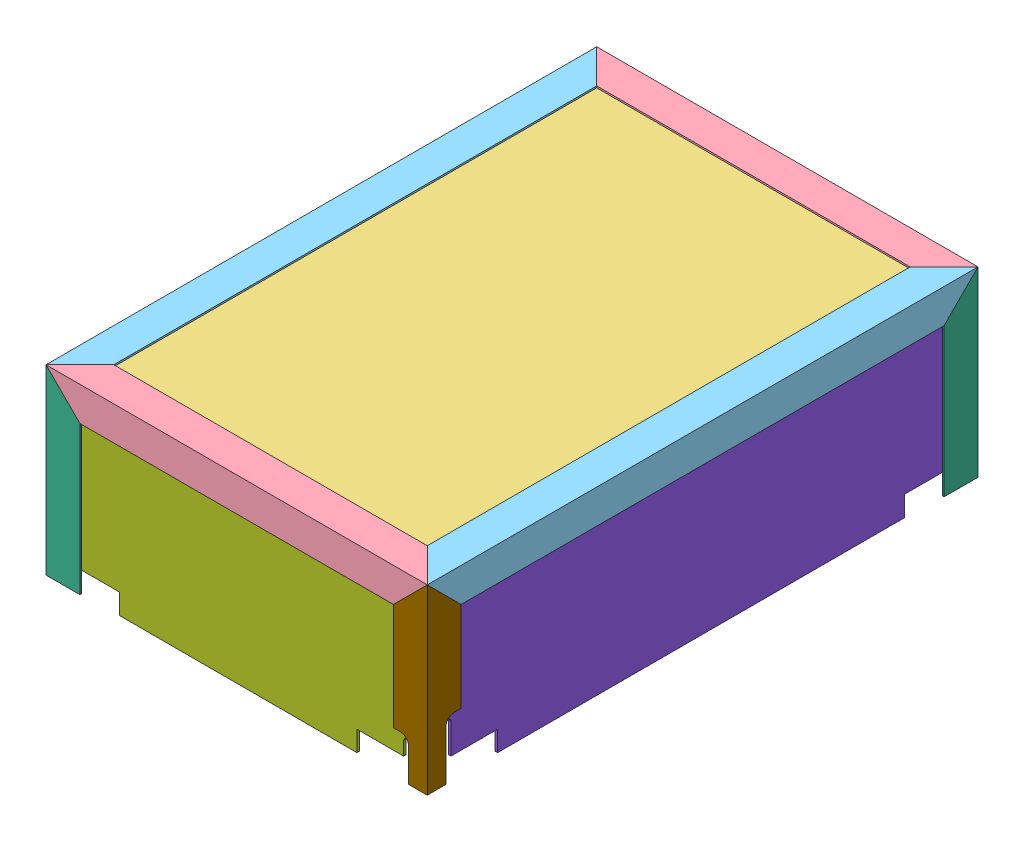
SolidWorks assembly couvercle, configuration Défaut. Lengths in mm.
Overall size (450 215 650).
13 component instances, 9 part files, 31 mates.
Components (placement in the parent):
- plaque_acrylique_680x210-2: plaque_acrylique_680x210 [Défaut] at (-583.1966 1.1201 -270.8343) x (0 0 -1) z (1 0 0) size (640 210 3)
- plaque_acrylique_380x210-2: plaque_acrylique_380x210 [Défaut] at (-330.1966 1.1201 -613.8343) size (440 210 3)
- plaque_acrylique_380x680-1: plaque_acrylique_380x680 [Défaut] at (-330.1966 106.1201 -270.8343) x (1 0 0) z (0 1 0) size (440 640 3)
- eclisse_40x40x404_bisote_x2-1: eclisse_40x40x404_bisote_x2 [Défaut] at (-135.1966 91.0065 -595.8343) x (0 0 1) z (0 -1 0) size (40 450 40)
- eclisse_40x40x704_bisote_x2-1: eclisse_40x40x704_bisote_x2 [Défaut] at (-155.3102 91.1201 -615.8343) x (0 -1 0) z (-1 0 0) size (40 650 40)
- eclisse_40x40x404_bisote_x2-2: eclisse_40x40x404_bisote_x2 [Défaut] at (-585.1966 91.0065 14.1657) x (0 0 -1) z (0 -1 0) size (40 450 40)
- eclisse_40x40x704_bisote_x2-2: eclisse_40x40x704_bisote_x2 [Défaut] at (-565.1966 91.0065 -615.8343) x (1 0 0) z (0 -1 0) size (40 650 40)
- eclisse_40x40x222_bisote_x1-1: eclisse_40x40x222_bisote_x1 [Défaut] at (-565.083 111.1201 -595.8343) x (0 0 1) z (1 0 0) size (40 215 40)
- eclisse_40x40x222_bisote_x1-2: eclisse_40x40x222_bisote_x1 [Défaut] at (-155.1966 111.1201 -595.7207) x (-1 0 0) z (0 0 1) size (40 215 40)
- eclisse_40x40x222_bisote_x1-4: eclisse_40x40x222_bisote_x1 [Défaut] at (-565.1966 111.1201 14.052) x (1 0 0) z (0 0 -1) size (40 215 40)
- plaque_acrylique_380x210_Moteur-1: plaque_acrylique_380x210_Moteur [Défaut] at (-330.1966 1.1201 29.1657) size (440 210 3)
- plaque_acrylique_680x210_moteur-1: plaque_acrylique_680x210_moteur [Défaut] at (-140.1966 1.1201 -270.8343) x (0 0 -1) z (1 0 0) size (640 210 3)
- eclisse_40x40x222_bisote_x1_Moteur-1: eclisse_40x40x222_bisote_x1_Moteur [Défaut] at (-155.3102 111.1201 14.1657) x (0 0 -1) z (-1 0 0) size (40 215 40)
Mates (geometry in assembly coordinates):
- Coïncidente1: coincident anti-aligned: plane of plaque_acrylique_380x680-1 through (-330.1966 109.1201 -270.8343) normal (0 1 0); plane of eclisse_40x40x704_bisote_x2-1 through (-137.1966 109.1201 34.1657) normal (0 -1 0)
- Coïncidente2: coincident anti-aligned: plane of eclisse_40x40x704_bisote_x2-1 through (-137.1966 109.1201 34.1657) normal (-1 0 0); plane of plaque_acrylique_680x210_moteur-1 through (-137.1966 1.1201 -270.8343) normal (1 0 0)
- Coïncidente3: coincident anti-aligned: plane of plaque_acrylique_380x210-2 through (-330.1966 1.1201 -613.8343) normal (0 0 -1); plane of eclisse_40x40x404_bisote_x2-1 through (-585.1966 109.1201 -613.8343) normal (0 0 1)
- Coïncidente4: coincident anti-aligned: plane of plaque_acrylique_380x680-1 through (-330.1966 109.1201 -270.8343) normal (0 1 0); plane of eclisse_40x40x404_bisote_x2-1 through (-585.1966 109.1201 -613.8343) normal (0 -1 0)
- Coïncidente5: coincident anti-aligned: plane of plaque_acrylique_680x210-2 through (-583.1966 1.1201 -270.8343) normal (-1 0 0); plane of eclisse_40x40x704_bisote_x2-2 through (-583.1966 109.1201 34.1657) normal (1 0 0)
- Coïncidente6: coincident anti-aligned: plane of plaque_acrylique_380x680-1 through (-330.1966 109.1201 -270.8343) normal (0 1 0); plane of eclisse_40x40x704_bisote_x2-2 through (-583.1966 109.1201 34.1657) normal (0 -1 0)
- Coïncidente7: coincident anti-aligned: plane of eclisse_40x40x404_bisote_x2-2 through (-135.1966 109.1201 32.1657) normal (0 0 -1); plane of plaque_acrylique_380x210_Moteur-1 through (-330.1966 1.1201 32.1657) normal (0 0 1)
- Coïncidente9: coincident anti-aligned: plane of plaque_acrylique_380x210_Moteur-1 through (-330.1966 1.1201 32.1657) normal (0 0 1); plane of eclisse_40x40x222_bisote_x1_Moteur-1 through (-137.1966 -103.8799 32.1657) normal (0 0 -1)
- Coïncidente10: coincident anti-aligned: plane of plaque_acrylique_680x210_moteur-1 through (-137.1966 1.1201 -270.8343) normal (1 0 0); plane of eclisse_40x40x222_bisote_x1_Moteur-1 through (-137.1966 -103.8799 32.1657) normal (-1 0 0)
- Coïncidente11: coincident anti-aligned: plane of plaque_acrylique_380x210-2 through (-330.1966 1.1201 -613.8343) normal (0 0 -1); plane of eclisse_40x40x222_bisote_x1-2 through (-137.1966 -103.8799 -613.8343) normal (0 0 1)
- Coïncidente12: coincident anti-aligned: plane of eclisse_40x40x222_bisote_x1-2 through (-137.1966 -103.8799 -613.8343) normal (-1 0 0); plane of plaque_acrylique_680x210_moteur-1 through (-137.1966 1.1201 -270.8343) normal (1 0 0)
- Coïncidente13: coincident anti-aligned: plane of plaque_acrylique_680x210-2 through (-583.1966 1.1201 -270.8343) normal (-1 0 0); plane of eclisse_40x40x222_bisote_x1-1 through (-583.1966 -103.8799 -613.8343) normal (1 0 0)
- Coïncidente14: coincident anti-aligned: plane of plaque_acrylique_380x210-2 through (-330.1966 1.1201 -613.8343) normal (0 0 -1); plane of eclisse_40x40x222_bisote_x1-1 through (-583.1966 -103.8799 -613.8343) normal (0 0 1)
- Coïncidente15: coincident anti-aligned: plane of eclisse_40x40x222_bisote_x1-4 through (-583.1966 -103.8799 32.1657) normal (0 0 -1); plane of plaque_acrylique_380x210_Moteur-1 through (-330.1966 1.1201 32.1657) normal (0 0 1)
- Coïncidente16: coincident anti-aligned: plane of plaque_acrylique_680x210-2 through (-583.1966 1.1201 -270.8343) normal (-1 0 0); plane of eclisse_40x40x222_bisote_x1-4 through (-583.1966 -103.8799 32.1657) normal (1 0 0)
- Coïncidente19: coincident anti-aligned: line of plaque_acrylique_380x210_Moteur-1 through (-140.1966 -25.8799 29.1657) axis (0 1 0); line of plaque_acrylique_680x210_moteur-1 through (-140.1966 106.1201 29.1657) axis (0 -1 0)
- Coïncidente21: coincident aligned: line of plaque_acrylique_680x210-2 through (-580.1966 106.1201 29.1657) axis (0 -1 0); line of plaque_acrylique_380x210_Moteur-1 through (-580.1966 106.1201 29.1657) axis (0 -1 0)
- Coïncidente23: coincident anti-aligned: line of plaque_acrylique_680x210-2 through (-580.1966 -25.8799 -610.8343) axis (0 1 0); line of plaque_acrylique_380x210-2 through (-580.1966 106.1201 -610.8343) axis (0 -1 0)
- Coïncidente28: coincident anti-aligned: line of plaque_acrylique_380x680-1 through (-580.1966 106.1201 29.1657) axis (1 0 0); line of plaque_acrylique_380x210_Moteur-1 through (-140.1966 106.1201 29.1657) axis (-1 0 0)
- Coïncidente29: coincident aligned: line of plaque_acrylique_680x210-2 through (-580.1966 106.1201 -610.8343) axis (0 0 1); line of plaque_acrylique_380x680-1 through (-580.1966 106.1201 -610.8343) axis (0 0 1)
- Coïncidente30: coincident anti-aligned: plane of plaque_acrylique_380x680-1 through (-330.1966 109.1201 -270.8343) normal (0 1 0); plane of eclisse_40x40x404_bisote_x2-2 through (-135.1966 109.1201 32.1657) normal (0 -1 0)
- Coïncidente31: coincident anti-aligned: line of eclisse_40x40x404_bisote_x2-2 through (-135.1966 111.1201 34.1657) axis (-0.707107 -0.707107 0); line of eclisse_40x40x222_bisote_x1_Moteur-1 through (-175.1966 71.1201 34.1657) axis (0.707107 0.707107 0)
- Coïncidente32: coincident anti-aligned: line of eclisse_40x40x704_bisote_x2-1 through (-135.1966 71.1201 -5.8343) axis (0 0.707107 0.707107); line of eclisse_40x40x222_bisote_x1_Moteur-1 through (-135.1966 111.1201 34.1657) axis (0 -0.707107 -0.707107)
- Coïncidente35: coincident anti-aligned: line of eclisse_40x40x404_bisote_x2-2 through (-545.1966 71.1201 34.1657) axis (-0.707107 0.707107 0); line of eclisse_40x40x222_bisote_x1-4 through (-585.1966 111.1201 34.1657) axis (0.707107 -0.707107 0)
- Coïncidente36: coincident anti-aligned: line of eclisse_40x40x704_bisote_x2-2 through (-585.1966 111.1201 34.1657) axis (0 -0.707107 -0.707107); line of eclisse_40x40x222_bisote_x1-4 through (-585.1966 71.1201 -5.8343) axis (0 0.707107 0.707107)
- Coïncidente37: coincident anti-aligned: line of eclisse_40x40x404_bisote_x2-2 through (-585.1966 111.1201 34.1657) axis (0.707107 0 -0.707107); line of eclisse_40x40x704_bisote_x2-2 through (-545.1966 111.1201 -5.8343) axis (-0.707107 0 0.707107)
- Coïncidente38: coincident anti-aligned: line of eclisse_40x40x404_bisote_x2-1 through (-545.1966 111.1201 -575.8343) axis (-0.707107 0 -0.707107); line of eclisse_40x40x704_bisote_x2-2 through (-585.1966 111.1201 -615.8343) axis (0.707107 0 0.707107)
- Coïncidente39: coincident anti-aligned: line of eclisse_40x40x704_bisote_x2-2 through (-585.1966 71.1201 -575.8343) axis (0 0.707107 -0.707107); line of eclisse_40x40x222_bisote_x1-1 through (-585.1966 111.1201 -615.8343) axis (0 -0.707107 0.707107)
- Coïncidente40: coincident anti-aligned: line of eclisse_40x40x404_bisote_x2-1 through (-175.1966 71.1201 -615.8343) axis (0.707107 0.707107 0); line of eclisse_40x40x222_bisote_x1-2 through (-135.1966 111.1201 -615.8343) axis (-0.707107 -0.707107 0)
- Coïncidente41: coincident: line of plaque_acrylique_380x210-2 through (-140.1966 106.1201 -610.8343) axis (-1 0 0); plane of plaque_acrylique_380x680-1 through (-330.1966 106.1201 -270.8343) normal (0 -1 0)
- Coïncidente42: coincident: plane of plaque_acrylique_380x680-1 through (-330.1966 106.1201 -270.8343) normal (0 -1 0); line of plaque_acrylique_680x210_moteur-1 through (-140.1966 106.1201 -610.8343) axis (0 0 1)
